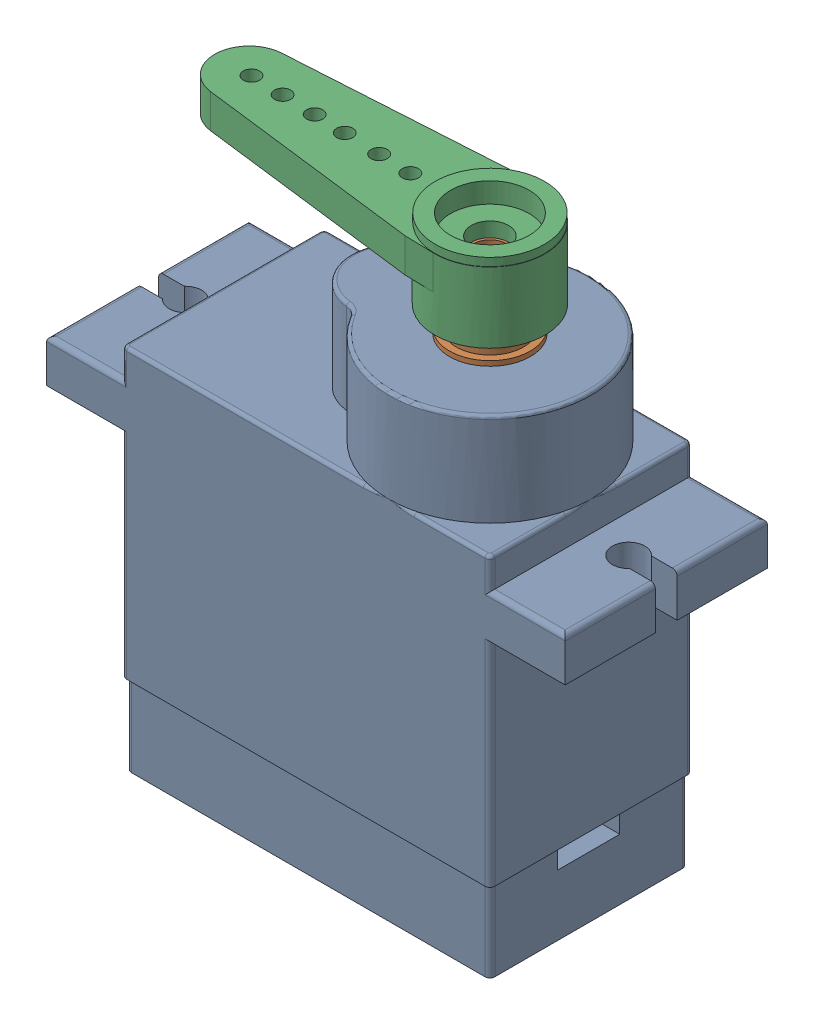
SolidWorks assembly assembly, configuration Default. Lengths in mm.
Overall size (32.05 34.95 12.5).
3 component instances, 3 part files, 4 mates.
Components (placement in the parent):
- body-1: body [Default] at origin size (32.05 28.5 12.5)
- shaft-1: shaft [Default] at (16.5 28.5 -6.25) x (0.786985 0 0.616972) z (-0.616972 0 0.786985) size (5 4.3 5)
- horn-1: horn [Default] at (16.5 34.45 -6.25) x (0.999514 0 0.031181) z (0.031181 0 -0.999514) size (20.9 4.85 6.82)
Mates (geometry in assembly coordinates):
- Coincident1: coincident anti-aligned: plane of MG90servo_body-1 through (16.5 28.5 -6.25) normal (0 1 0); plane of MG90servo_shaft-1 through (16.5 28.5 -6.25) normal (0 -1 0)
- Concentric2: concentric aligned: cylinder of MG90servo_body-1 through (16.5 26.5 -6.25) axis (0 1 0) radius 0.5; cylinder of MG90servo_shaft-1 through (16.5 29.3 -6.25) axis (0 1 0) radius 1
- Coincident3: coincident anti-aligned: plane of MG90servo_shaft-1 through (16.5 32.8 -6.25) normal (0 1 0); plane of MG90servo_singleHorn-1 through (16.5 32.8 -6.25) normal (0 -1 0)
- Concentric4: concentric anti-aligned: cylinder of MG90servo_shaft-1 through (16.5 29.3 -6.25) axis (0 1 0) radius 1; cylinder of MG90servo_singleHorn-1 through (16.5 32.8 -6.25) axis (0 -1 0) radius 2.25
